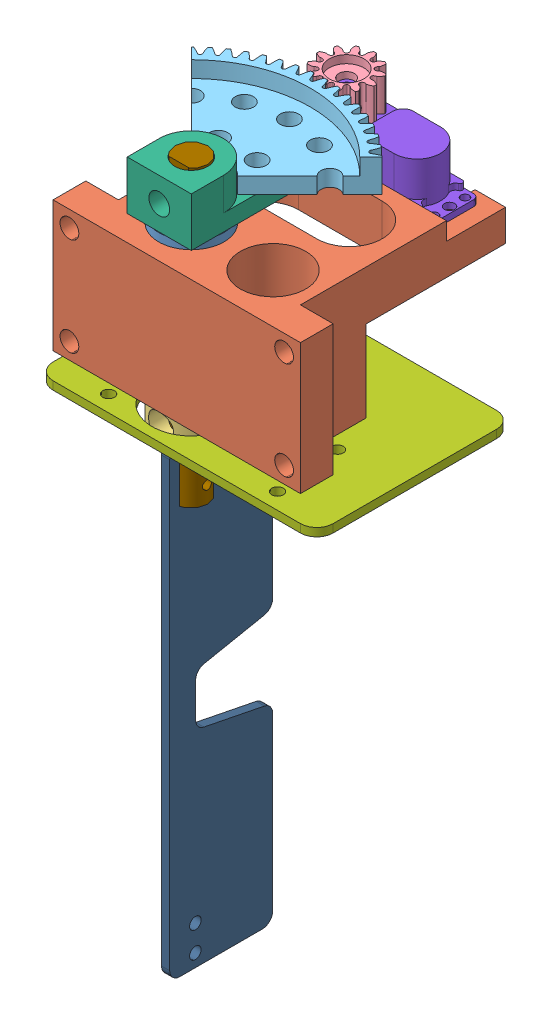
SolidWorks assembly Jet vane unit, configuration Default. Lengths in mm.
Overall size (55.33 136.31 46.19).
11 component instances, 10 part files, 24 mates.
Components (placement in the parent):
- Bearing, flanged sleeve, 1_4in shaft_z-1: Bearing, flanged sleeve, 1_4in shaft_z [默认] at (70.4445 83.0834 33.9634) x (1 0 0) z (0 -1 0) size (12.7 12.7 6.35)
- block_z-1: block_z [默认] at (70.4445 56.0959 33.9634) size (48.05 25.4 46.19)
- collar_z-1: collar_z [默认] at (70.4445 50.5397 33.9634) size (12.7 7.94 12.7)
- gear_12_teeth-1: gear_12_teeth [默认] at (70.4445 92.3544 3.8009) x (1 0 0) z (0 -1 0) size (11.11 11.13 6.35)
- gear_64_teeth-1: gear_64_teeth [默认] at (70.4445 86.2584 33.9634) x (0.382683 0 -0.92388) z (0 1 0) size (23.76 34.22 6.35)
- gear_mount-1: gear_mount [默认] at (70.4445 56.0959 33.9634) size (12.45 9.53 28.45)
- heat_shiled-1: heat_shiled [默认] at (70.4445 54.2297 33.9634) size (54.4 1.59 38.1)
- 舵机-1: 舵机 [默认] at (70.4445 79.2044 3.8009) x (1 0 0) z (0 1 0) size (29 9 20.05)
- Bearing, flanged sleeve, 1_4in shaft_z-2: Bearing, flanged sleeve, 1_4in shaft_z [默认] at (70.4445 54.5084 33.9634) x (-0.837169 0 -0.546944) z (0 1 0) size (12.7 12.7 6.35)
- vane_shaft-1: vane_shaft [Default] at (70.4445 92.9259 33.9634) x (1 0 0) z (0 0 -1) size (6.35 57.15 6.35)
- vane_a-2: vane_a [默认] at (70.4442 57.3659 33.9634) size (1.59 89.95 20)
Mates (geometry in assembly coordinates):
- 重合4: coincident anti-aligned: plane of block_z-1 through (65.3945 78.0044 -2.6991) normal (0 1 0); plane of 舵机-1 through (65.6445 78.0044 -0.6991) normal (0 -1 0)
- 同心4: concentric aligned: cylinder of block_z-1 through (63.8445 71.9084 3.8009) axis (0 -1 0) radius 0.85; cylinder of 舵机-1 through (63.8445 78.0044 3.8009) axis (0 -1 0) radius 1
- 同心5: concentric aligned: cylinder of block_z-1 through (90.4445 71.9084 3.8009) axis (0 -1 0) radius 0.85; cylinder of 舵机-1 through (90.4445 78.0044 3.8009) axis (0 -1 0) radius 1
- 重合5: coincident anti-aligned: plane of gear_12_teeth-1 through (70.0053 86.0044 9.0212) normal (0 -1 0); plane of 舵机-1 through (65.6445 86.0044 -0.6991) normal (0 1 0)
- 同心6: concentric anti-aligned: cylinder of gear_12_teeth-1 through (70.4445 89.5604 3.8009) axis (0 -1 0) radius 1.5; cylinder of 舵机-1 through (70.4445 89.3544 3.8009) axis (0 1 0) radius 1.075
- 重合8: coincident anti-aligned: plane of gear_64_teeth-1 through (70.4445 86.2584 33.9634) normal (0 -1 0); plane of gear_mount-1 through (70.4445 86.2584 33.9634) normal (0 1 0)
- 同心9: concentric anti-aligned: cylinder of gear_64_teeth-1 through (74.1868 89.4334 24.9287) axis (0 1 0) radius 1.778; cylinder of gear_mount-1 through (74.1868 83.0834 24.9287) axis (0 -1 0) radius 1.3526
- 同心10: concentric anti-aligned: cylinder of gear_64_teeth-1 through (66.7022 89.4334 24.9287) axis (0 1 0) radius 1.778; cylinder of gear_mount-1 through (66.7022 83.0834 24.9287) axis (0 -1 0) radius 1.3526
- 重合10: coincident anti-aligned: plane of collar_z-1 through (70.4445 54.5084 33.9634) normal (0 1 0); plane of Bearing, flanged sleeve, 1_4in shaft_z-2 through (67.7759 54.5084 32.2199) normal (0 -1 0)
- 重合11: coincident anti-aligned: plane of Bearing, flanged sleeve, 1_4in shaft_z-1 through (73.6322 83.0834 33.9634) normal (0 1 0); plane of gear_mount-1 through (70.4445 83.0834 33.9634) normal (0 -1 0)
- 重合12: coincident anti-aligned: plane of Bearing, flanged sleeve, 1_4in shaft_z-1 through (76.7945 81.4959 33.9634) normal (0 -1 0); plane of block_z-1 through (77.1445 81.4959 20.3946) normal (0 1 0)
- 同心14: concentric anti-aligned: cylinder of collar_z-1 through (70.4445 46.5709 33.9634) axis (0 1 0) radius 6.35; cylinder of heat_shiled-1 through (70.4445 51.0547 33.9634) axis (0 -1 0) radius 7.62
- 同心15: concentric aligned: cylinder of block_z-1 through (92.3195 56.0959 27.4384) axis (0 -1 0) radius 0.889; cylinder of heat_shiled-1 through (92.3195 51.0547 27.4384) axis (0 -1 0) radius 1.1303
- 同心16: concentric aligned: cylinder of block_z-1 through (61.9695 56.0959 27.4384) axis (0 -1 0) radius 0.889; cylinder of heat_shiled-1 through (61.9695 51.0547 27.4384) axis (0 -1 0) radius 1.1303
- 同心19: concentric anti-aligned: cylinder of collar_z-1 through (70.4445 46.5709 33.9634) axis (0 -1 0) radius 3.175; cylinder of vane_shaft-1 through (70.4445 35.7759 33.9634) axis (0 1 0) radius 3.175
- 同心20: concentric anti-aligned: cylinder of Bearing, flanged sleeve, 1_4in shaft_z-2 through (70.4445 60.8584 33.9634) axis (0 -1 0) radius 3.1877; cylinder of vane_shaft-1 through (70.4445 35.7759 33.9634) axis (0 1 0) radius 3.175
- 同心21: concentric aligned: cylinder of block_z-1 through (70.4445 81.4959 33.9634) axis (0 1 0) radius 4.7625; cylinder of vane_shaft-1 through (70.4445 35.7759 33.9634) axis (0 1 0) radius 3.175
- 重合15: coincident anti-aligned: plane of block_z-1 through (70.4445 56.0959 33.9634) normal (0 -1 0); plane of Bearing, flanged sleeve, 1_4in shaft_z-2 through (65.1285 56.0959 30.4903) normal (0 1 0)
- 同心22: concentric aligned: cylinder of Bearing, flanged sleeve, 1_4in shaft_z-1 through (70.4445 76.7334 33.9634) axis (0 1 0) radius 3.1877; cylinder of vane_shaft-1 through (70.4445 35.7759 33.9634) axis (0 1 0) radius 3.175
- 同心23: concentric aligned: cylinder of gear_mount-1 through (70.4445 92.6084 33.9634) axis (0 1 0) radius 3.2004; cylinder of vane_shaft-1 through (70.4445 35.7759 33.9634) axis (0 1 0) radius 3.175
- 平行1: parallel aligned: plane of gear_mount-1 through (64.2215 83.0834 40.1864) normal (0 0 1); plane of vane_shaft-1 through (68.4634 84.3529 36.3446) normal (0 0 1)
- 重合16: coincident anti-aligned: plane of vane_shaft-1 through (71.2385 46.5709 37.1384) normal (-1 0 0); plane of vane_a-2 through (71.2385 44.5709 20.9634) normal (1 0 0)
- 同心24: concentric aligned: cylinder of vane_shaft-1 through (82.0335 44.0709 33.9634) axis (-1 0 0) radius 0.889; cylinder of vane_a-2 through (71.2385 44.0709 33.9634) axis (-1 0 0) radius 1.1303
- 同心25: concentric aligned: cylinder of vane_shaft-1 through (82.0335 39.0709 33.9634) axis (-1 0 0) radius 0.889; cylinder of vane_a-2 through (71.2385 39.0709 33.9634) axis (-1 0 0) radius 1.1303
